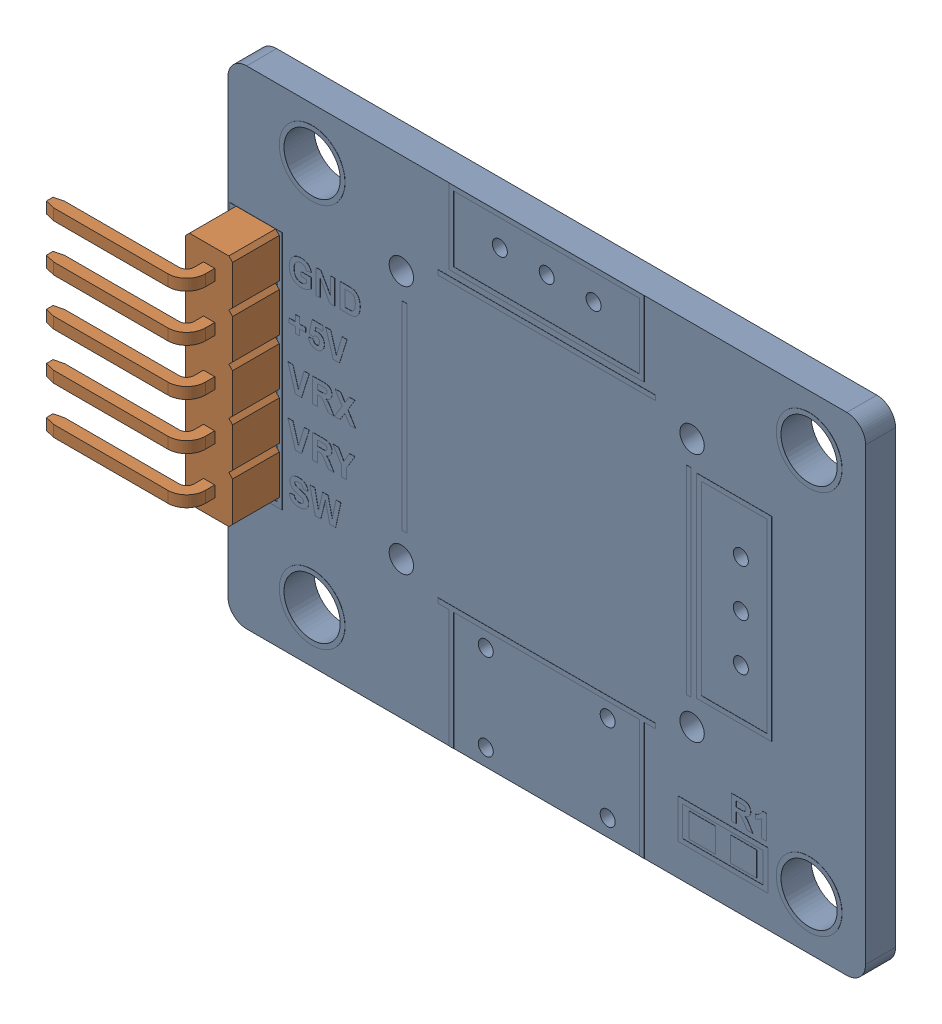
SolidWorks assembly BaseBoard, configuration Default. Lengths in mm.
Overall size (39.8 26 7).
2 component instances, 2 part files, 0 mates.
Components (placement in the parent):
- PCB-1: PCB [Default] at origin size (34 26 1.61)
- 5x_Ang_Conn-1: 5x_Ang_Conn [Default] at (-15.5 -1 1.6) size (8.55 12.5 7)
